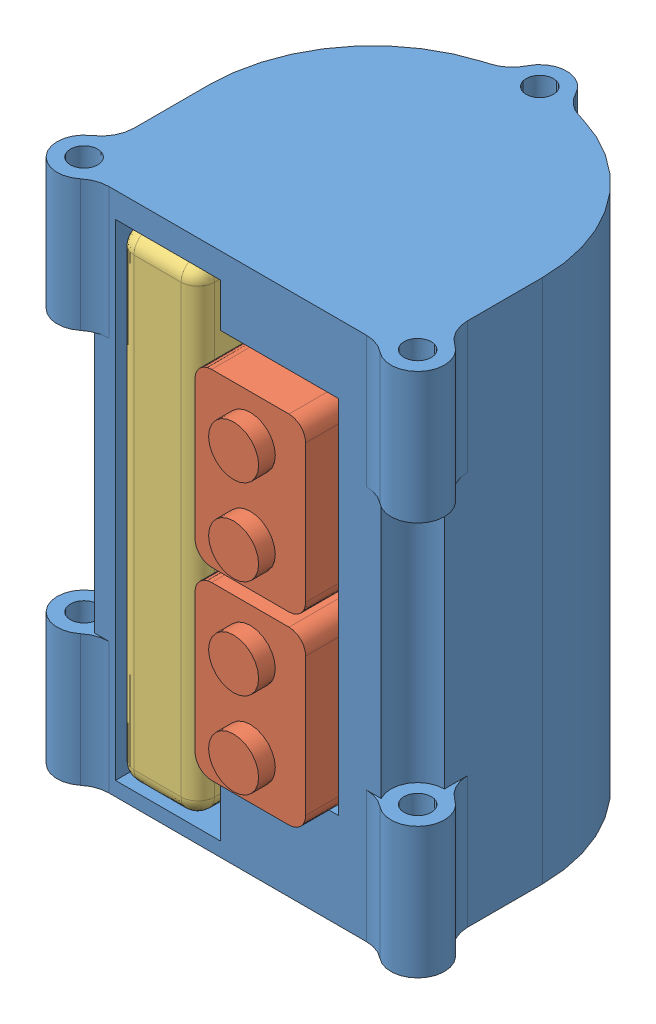
SolidWorks assembly S1B_Flight_Power_Stack_Assy, configuration Default. Lengths in mm.
Overall size (58.99 80 57.67).
4 component instances, 3 part files, 9 mates.
Components (placement in the parent):
- S1B_Power_Stack-1: S1B_Power_Stack [Default] at (-4.1095 89.1616 81.6309) size (58.99 80 52.18)
- S1B_9V Battery-1: S1B_9V Battery [Default] at (-5.5953 51.787 105.8736) x (0 0 -1) z (0 -1 0) size (47.57 16.87 26.11)
- S1B_LiPo_A1-1: S1B_LiPo_A1 [Default] at (-22.7297 11.3191 64.2994) x (0 1 0) z (0 0 -1) size (72.97 12.27 33.73)
- S1B_9V Battery-2: S1B_9V Battery [Default] at (-5.5953 23.6758 105.8736) x (0 0 -1) z (0 -1 0) size (47.57 16.87 26.11)
Mates (geometry in assembly coordinates):
- Coincident1: coincident aligned: plane of 9V Battery-1 through (11.2703 51.787 58.2994) normal (0 0 -1); plane of 9V Battery-2 through (11.2703 23.6758 58.2994) normal (0 0 -1)
- Distance1: distance = 2 mm anti-aligned: plane of 9V Battery-1 through (11.2703 51.787 105.8736) normal (0 -1 0); plane of 9V Battery-2 through (11.2703 49.787 105.8736) normal (0 1 0)
- Coincident5: coincident aligned: plane of 9V Battery-1 through (11.2703 51.787 105.8736) normal (1 0 0); plane of 9V Battery-2 through (11.2703 23.6758 105.8736) normal (1 0 0)
- Coincident7: coincident anti-aligned: plane of S1B_Power_Stack-1 through (11.2703 78.6758 58.2994) normal (-1 0 0); plane of 9V Battery-1 through (11.2703 51.787 105.8736) normal (1 0 0)
- Coincident11: coincident anti-aligned: plane of S1B_Power_Stack-1 through (11.2703 23.6758 58.2994) normal (0 1 0); plane of 9V Battery-2 through (11.2703 23.6758 105.8736) normal (0 -1 0)
- Coincident12: coincident anti-aligned: plane of S1B_Power_Stack-1 through (-22.7297 89.1616 64.2994) normal (1 0 0); plane of LiPo_A1-1 through (-22.7297 11.3191 64.2994) normal (-1 0 0)
- Coincident13: coincident anti-aligned: plane of S1B_Power_Stack-1 through (-4.1095 89.1616 64.2994) normal (0 0 1); plane of LiPo_A1-1 through (-10.4615 11.3191 64.2994) normal (0 0 -1)
- Coincident14: coincident anti-aligned: plane of S1B_Power_Stack-1 through (-4.1095 11.3191 64.2994) normal (0 1 0); plane of LiPo_A1-1 through (-10.4615 11.3191 64.2994) normal (0 -1 0)
- Coincident16: coincident anti-aligned: plane of S1B_Power_Stack-1 through (-4.1095 89.1616 58.2994) normal (0 0 1); plane of 9V Battery-2 through (11.2703 23.6758 58.2994) normal (0 0 -1)
